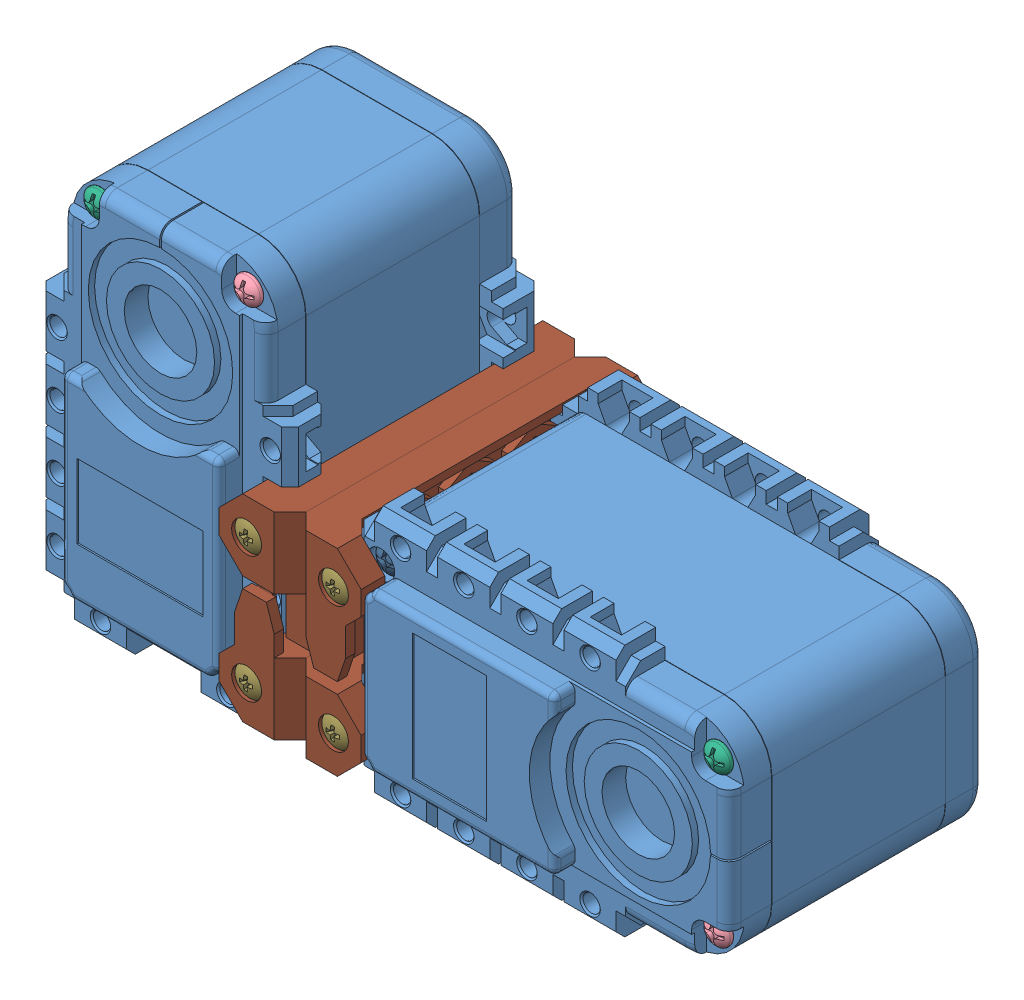
SolidWorks assembly avant-bras, configuration Défaut. Lengths in mm.
Overall size (88.04 50.04 38.67).
41 component instances, 14 part files, 24 mates.
Components (placement in the parent):
- ASSY_DUMMY___-1: ASSY_DUMMY___ [Défaut] at (-16.412 -6.0202 3.6059) size (32 50.04 38.67)
- DC04_B01_INSERT_M3-1: DC04_B01_INSERT_M3 [Défaut] at (-16.412 -6.0202 3.6059) size (4.98 4.98 7)
- DX124_SCREW-COVER___-1: DX124_SCREW-COVER___ [Défaut] at (-16.412 -6.0202 3.6059) size (3.56 3.56 30.67)
  - DX124_SCREW-COVER___-1: DX124_SCREW-COVER___ [Défaut] at origin size (2 2 6)
  - DX124_SCREW-COVER___-1-1: DX124_SCREW-COVER___-1 [Défaut] at origin size (3.56 3.56 30.67)
- DX124_SCREW-COVER____1-1: DX124_SCREW-COVER____1 [Défaut] at (-16.412 -6.0202 3.6059) size (3.56 3.56 30.67)
  - DX124_SCREW-COVER____1-1: DX124_SCREW-COVER____1 [Défaut] at origin size (2 2 6)
  - DX124_SCREW-COVER____1-1-1: DX124_SCREW-COVER____1-1 [Défaut] at origin size (3.56 3.56 30.67)
- DX124_SCREW-COVER____2-1: DX124_SCREW-COVER____2 [Défaut] at (-16.412 -6.0202 3.6059) size (3.56 3.56 30.67)
  - DX124_SCREW-COVER____2-1: DX124_SCREW-COVER____2 [Défaut] at origin size (2 2 6)
  - DX124_SCREW-COVER____2-1-1: DX124_SCREW-COVER____2-1 [Défaut] at origin size (3.56 3.56 30.67)
- DX124_SCREW-COVER____3-1: DX124_SCREW-COVER____3 [Défaut] at (-16.412 -6.0202 3.6059) size (3.56 3.56 30.67)
  - DX124_SCREW-COVER____3-1: DX124_SCREW-COVER____3 [Défaut] at origin size (2 2 6)
  - DX124_SCREW-COVER____3-1-1: DX124_SCREW-COVER____3-1 [Défaut] at origin size (3.56 3.56 30.67)
- Pièce1^avant-bras-1: Pièce1^avant-bras [Défaut] at origin (virtual)
- F3-1: F3 [Défaut] at (2.588 -28.5202 3.6059) x (0 1 0) z (0 0 1) size (25 9 38)
- AX-12A-1: AX-12A [Défaut] at (45.0106 -28.2116 4.921) x (0 -1 0) z (0 0 1) size (32 53.04 38.67)
  - ASSY_DUMMY___-1: ASSY_DUMMY___ [Défaut] at (0.3086 -0.9226 -1.3151) size (32 50.04 38.67)
  - DC04_B01_INSERT_M3-1: DC04_B01_INSERT_M3 [Défaut] at (0.3086 -0.9226 -1.3151) size (4.98 4.98 7)
  - DX124_SCREW-COVER___-1: DX124_SCREW-COVER___ [Défaut] at (0.3086 -0.9226 -1.3151) size (3.56 3.56 30.67)
    - DX124_SCREW-COVER___-1: DX124_SCREW-COVER___ [Défaut] at origin size (2 2 6)
    - DX124_SCREW-COVER___-1-1: DX124_SCREW-COVER___-1 [Défaut] at origin size (3.56 3.56 30.67)
  - DX124_SCREW-COVER____1-1: DX124_SCREW-COVER____1 [Défaut] at (0.3086 -0.9226 -1.3151) size (3.56 3.56 30.67)
    - DX124_SCREW-COVER____1-1: DX124_SCREW-COVER____1 [Défaut] at origin size (2 2 6)
    - DX124_SCREW-COVER____1-1-1: DX124_SCREW-COVER____1-1 [Défaut] at origin size (3.56 3.56 30.67)
  - DX124_SCREW-COVER____2-1: DX124_SCREW-COVER____2 [Défaut] at (0.3086 -0.9226 -1.3151) size (3.56 3.56 30.67)
    - DX124_SCREW-COVER____2-1: DX124_SCREW-COVER____2 [Défaut] at origin size (2 2 6)
    - DX124_SCREW-COVER____2-1-1: DX124_SCREW-COVER____2-1 [Défaut] at origin size (3.56 3.56 30.67)
  - DX124_SCREW-COVER____3-1: DX124_SCREW-COVER____3 [Défaut] at (0.3086 -0.9226 -1.3151) size (3.56 3.56 30.67)
    - DX124_SCREW-COVER____3-1: DX124_SCREW-COVER____3 [Défaut] at origin size (2 2 6)
    - DX124_SCREW-COVER____3-1-1: DX124_SCREW-COVER____3-1 [Défaut] at origin size (3.56 3.56 30.67)
  - Pièce1^AX-12A-1: Pièce1^AX-12A [Défaut] at origin (virtual)
  - F3-1: F3 [Défaut] at (0.3086 -42.4226 -1.3151) size (25 9 38)
  - vis M2-3: vis M2 [B18.6.7M - M2 x 0.4 x 2.5 Type I Cross Recessed PHMS --2.5N] at (-7.6914 -36.9226 17.8849) x (0 0 -1) z (1 0 0) size (4.08 4 4)
  - vis M2-4: vis M2 [B18.6.7M - M2 x 0.4 x 2.5 Type I Cross Recessed PHMS --2.5N] at (8.3086 -36.9226 17.8849) x (0 0 -1) z (1 0 0) size (4.08 4 4)
  - vis M2-5: vis M2 [B18.6.7M - M2 x 0.4 x 2.5 Type I Cross Recessed PHMS --2.5N] at (8.3086 -36.9226 -20.5151) x (0 0 1) z (-0.923728 -0.383049 0) size (4.08 4 4)
  - vis M2-6: vis M2 [B18.6.7M - M2 x 0.4 x 2.5 Type I Cross Recessed PHMS --2.5N] at (-7.6914 -36.9226 -20.5151) x (0 0 1) z (-0.923728 -0.383049 0) size (4.08 4 4)
- vis M2-1: vis M2 [B18.6.7M - M2 x 0.4 x 2.5 Type I Cross Recessed PHMS --2.5N] at (-2.912 -20.5202 -15.5941) x (0 0 1) z (0.923728 0.383049 0) size (4.08 4 4)
- vis M2-2: vis M2 [B18.6.7M - M2 x 0.4 x 2.5 Type I Cross Recessed PHMS --2.5N] at (-2.912 -36.5202 -15.5941) x (0 0 1) z (0.923728 0.383049 0) size (4.08 4 4)
- vis M2-3: vis M2 [B18.6.7M - M2 x 0.4 x 2.5 Type I Cross Recessed PHMS --2.5N] at (-2.912 -36.5202 22.8059) x (0 0 -1) z (-1 0 0) size (4.08 4 4)
- vis M2-4: vis M2 [B18.6.7M - M2 x 0.4 x 2.5 Type I Cross Recessed PHMS --2.5N] at (-2.912 -20.5202 22.8059) x (0 0 -1) z (-1 0 0) size (4.08 4 4)
Mates (geometry in assembly coordinates):
- Coaxiale4: concentric aligned: cylinder of ASSY_DUMMY___-1 through (-16.412 -6.0202 -7.7941) axis (0 0 -1) radius 2.15; cylinder of DC04_B01_INSERT_M3-1 through (-16.412 -6.0202 -11.7941) axis (0 0 -1) radius 2.15
- Coïncidente4: coincident anti-aligned: plane of ASSY_DUMMY___-1 through (-14.176 -3.7842 -7.7941) normal (0 0 -1); plane of DC04_B01_INSERT_M3-1 through (-13.8203 -3.4285 -7.7941) normal (0 0 1)
- Coaxiale9: concentric anti-aligned: cylinder of ASSY_DUMMY___-1 through (-25.912 2.4798 12.6059) axis (0 0 1) radius 1.035; cylinder of DX124_SCREW-COVER____1-1/DX124_SCREW-COVER____1-1-1 through (-25.912 2.4798 18.1059) axis (0 0 -1) radius 0.8
- Coaxiale10: concentric anti-aligned: cylinder of ASSY_DUMMY___-1 through (-6.912 2.4798 12.6059) axis (0 0 1) radius 1.035; cylinder of DX124_SCREW-COVER___-1/DX124_SCREW-COVER___-1-1 through (-6.912 2.4798 18.1059) axis (0 0 -1) radius 0.8
- Coaxiale11: concentric anti-aligned: cylinder of ASSY_DUMMY___-1 through (-26.912 -39.0202 18.1059) axis (0 0 1) radius 1.75; cylinder of DX124_SCREW-COVER____3-1/DX124_SCREW-COVER____3-1-1 through (-26.912 -39.0202 18.1059) axis (0 0 -1) radius 0.8
- Coaxiale12: concentric anti-aligned: cylinder of ASSY_DUMMY___-1 through (-5.912 -39.0202 12.6059) axis (0 0 1) radius 1.035; cylinder of DX124_SCREW-COVER____2-1/DX124_SCREW-COVER____2-1-1 through (-5.912 -39.0202 18.1059) axis (0 0 -1) radius 0.8
- Coïncidente6: coincident anti-aligned: plane of ASSY_DUMMY___-1 through (-29.7951 6.3568 18.1059) normal (0 0 1); plane of DX124_SCREW-COVER____2-1/DX124_SCREW-COVER____2-1-1 through (-7.6488 -37.2797 18.1059) normal (0 0 -1)
- Coïncidente7: coincident anti-aligned: plane of ASSY_DUMMY___-1 through (-29.7951 6.3568 18.1059) normal (0 0 1); plane of DX124_SCREW-COVER____3-1/DX124_SCREW-COVER____3-1-1 through (-28.6488 -37.2797 18.1059) normal (0 0 -1)
- Coïncidente8: coincident anti-aligned: plane of ASSY_DUMMY___-1 through (-29.7951 6.3568 18.1059) normal (0 0 1); plane of DX124_SCREW-COVER____1-1/DX124_SCREW-COVER____1-1-1 through (-27.6488 4.2203 18.1059) normal (0 0 -1)
- Coïncidente9: coincident anti-aligned: plane of ASSY_DUMMY___-1 through (-29.7951 6.3568 18.1059) normal (0 0 1); plane of DX124_SCREW-COVER___-1/DX124_SCREW-COVER___-1-1 through (-8.6488 4.2203 18.1059) normal (0 0 -1)
- Coïncidente10: coincident anti-aligned: plane of ASSY_DUMMY___-1 through (-31.908 -44.3032 19.6059) normal (0 0 1); plane of F3-1 through (-3.412 -25.0202 19.6059) normal (0 0 -1)
- Coaxiale15: concentric aligned: cylinder of ASSY_DUMMY___-1 through (-2.912 -36.5202 17.6059) axis (0 0 1) radius 1.1; cylinder of F3-1 through (-2.912 -36.5202 22.6059) axis (0 0 1) radius 1.05
- Coaxiale16: concentric aligned: cylinder of ASSY_DUMMY___-1 through (-2.912 -20.5202 17.6059) axis (0 0 1) radius 1.1; cylinder of F3-1 through (-2.912 -20.5202 22.6059) axis (0 0 1) radius 1.05
- Coïncidente11: coincident anti-aligned: plane of F3-1 through (2.588 -25.0202 -15.3941) normal (1 0 0); plane of AX-12A-1/F3-1 through (2.588 -32.0202 -15.3941) normal (-1 0 0)
- Coaxiale17: concentric anti-aligned: cylinder of F3-1 through (0.588 -36.5202 11.6059) axis (-1 0 0) radius 1.05; cylinder of AX-12A-1/F3-1 through (4.588 -36.5202 11.6059) axis (1 0 0) radius 1.05
- Coïncidente12: coincident aligned: plane of F3-1 through (0.728 -41.5202 22.6059) normal (0 0 1); plane of AX-12A-1/F3-1 through (4.448 -15.5202 22.6059) normal (0 0 1)
- Coaxiale19: concentric aligned: cylinder of F3-1 through (-2.912 -20.5202 -15.3941) axis (0 0 -1) radius 1.05; cylinder of vis M2-1 through (-2.912 -20.5202 -40.9941) axis (0 0 -1) radius 1
- Coïncidente13: coincident anti-aligned: plane of F3-1 through (-2.912 -19.4702 -13.9941) normal (0 0 -1); plane of vis M2-1 through (-2.5289 -21.4439 -13.9941) normal (0 0 1)
- Coaxiale20: concentric aligned: cylinder of F3-1 through (-2.912 -36.5202 -15.3941) axis (0 0 -1) radius 1.05; cylinder of vis M2-2 through (-2.912 -36.5202 -40.9941) axis (0 0 -1) radius 1
- Coïncidente14: coincident anti-aligned: plane of F3-1 through (-2.912 -35.4702 -13.9941) normal (0 0 -1); plane of vis M2-2 through (-2.5289 -37.4439 -13.9941) normal (0 0 1)
- Coaxiale21: concentric aligned: cylinder of F3-1 through (-2.912 -36.5202 22.6059) axis (0 0 1) radius 1.05; cylinder of vis M2-3 through (-2.912 -36.5202 48.2059) axis (0 0 1) radius 1
- Coïncidente15: coincident anti-aligned: plane of F3-1 through (-2.912 -35.4702 21.2059) normal (0 0 1); plane of vis M2-3 through (-2.912 -37.5202 21.2059) normal (0 0 -1)
- Coaxiale22: concentric aligned: cylinder of F3-1 through (-2.912 -20.5202 22.6059) axis (0 0 1) radius 1.05; cylinder of vis M2-4 through (-2.912 -20.5202 48.2059) axis (0 0 1) radius 1
- Coïncidente16: coincident anti-aligned: plane of F3-1 through (-2.912 -19.4702 21.2059) normal (0 0 1); plane of vis M2-4 through (-2.912 -21.5202 21.2059) normal (0 0 -1)
